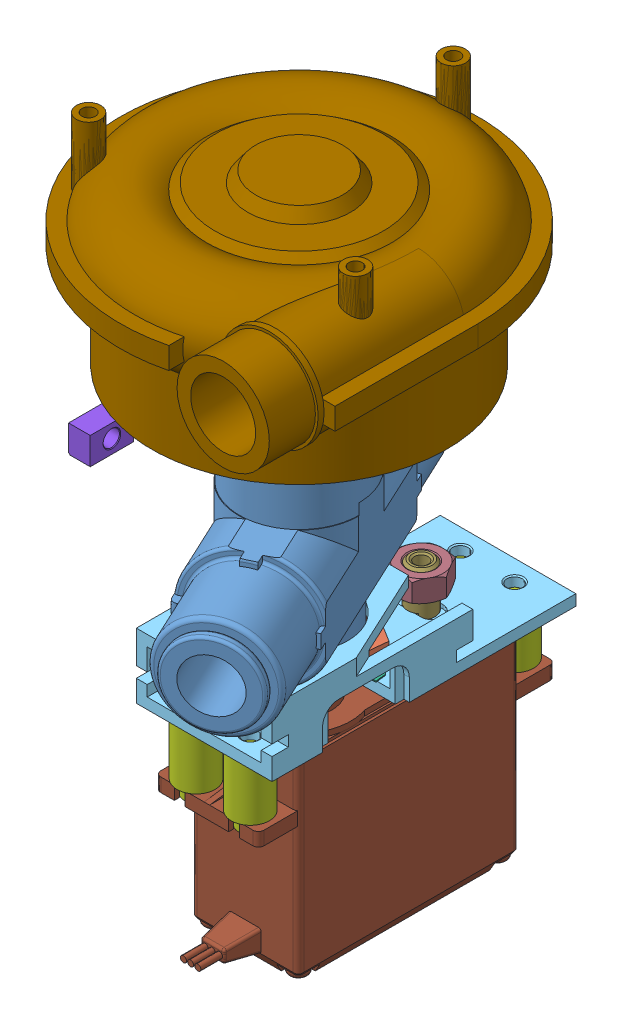
SolidWorks assembly компрессор_v3, configuration По умолчанию. Lengths in mm.
Overall size (66 124.61 75.54).
25 component instances, 20 part files, 46 mates.
Components (placement in the parent):
- 326-4F6SMC6SMC_WO_GRIP_CUT-1: 326-4F6SMC6SMC_WO_GRIP_CUT [По умолчанию] at (-17.3525 27.3268 -50.2596) x (0.422618 0 0.906308) z (0 -1 0) size (66.8 22.11 40.11)
- фланец_v3-1: фланец_v3 [По умолчанию] at (-3.2366 53.3268 5.012) x (1 0 0) z (0 1 0) (suppressed, hidden)
- гайка_18-1: гайка_18 [По умолчанию] at (-3.2366 14.83 -19.988) x (-0.866025 0 -0.5) z (-0.5 0 0.866025) size (24.25 4 21) (hidden)
- гайка_22-1: гайка_22 [По умолчанию] at (-3.2366 39.3268 -19.988) x (0.866025 0 -0.5) z (0.5 0 0.866025) (suppressed, hidden)
- apc10004_6_0-1: apc10004_6_0 [По умолчанию] at (15 66.2108 207.372) x (0.004188 0.999991 0) z (0 0 1) size (19.05 23.5 35.56) (suppressed, hidden)
  - APC10004-BODY-1: APC10004-BODY [По умолчанию] at origin size (19.05 19.05 35.56)
  - APC-LATCH_1-1: APC-LATCH_1 [По умолчанию] at origin size (15.11 23.5 12.49)
- ручка_крана_обрез-1: ручка_крана_обрез [По умолчанию] at (-3.2366 11.25 -19.988) x (0.678602 0 -0.734506) z (0.734506 0 0.678602) size (9.5 7 9.5)
- крестовина_2-1: крестовина_2 [По умолчанию] at (-3.2366 13.75 -19.988) x (0.418906 0 0.90803) z (0 -1 0) size (14 14 4.5)
- мостик_v5-1: мостик_v5 [По умолчанию] at (-3.2366 10.83 -2.488) x (-1 0 0) z (0 0 -1) size (25 12 56) (hidden)
- стрелка-1: стрелка [По умолчанию] at (-3.3741 8.436 -21.2304) x (-0.110025 0 -0.993929) z (0.993929 0 -0.110025) size (10 0.2 20.5) (hidden)
- EE-SX1107-1: EE-SX1107 [По умолчанию] at (6.2634 8.536 -16.9874) x (0 0 1) z (0 -1 0)
- EE-SX1107-2: EE-SX1107 [По умолчанию] at (6.2634 8.536 -22.9679) x (0 0 -1) z (0 1 0)
- сухарь1-1: сухарь1 [По умолчанию] at (9.2634 16.83 -43.488) x (0 0 1) z (-1 0 0) (suppressed, hidden)
- бобышка_серво-1: бобышка_серво [По умолчанию] at (1.7634 4.83 -5.988) x (-0.837169 0 -0.546944) z (-0.546944 0 0.837169) size (7 12.4 7)
- бобышка_серво-2: бобышка_серво [По умолчанию] at (1.7634 4.83 -54.688) x (-0.837169 0 -0.546944) z (-0.546944 0 0.837169) size (7 12.4 7)
- бобышка_серво-3: бобышка_серво [По умолчанию] at (-8.2366 4.83 -54.688) x (-0.837169 0 -0.546944) z (-0.546944 0 0.837169) size (7 12.4 7)
- бобышка_серво-4: бобышка_серво [По умолчанию] at (-8.2366 4.83 -5.988) x (-0.837169 0 -0.546944) z (-0.546944 0 0.837169) size (7 12.4 7)
- сухарь2-1: сухарь2 [По умолчанию] at (-20.7366 16.83 -2.488) x (0 0 -1) z (1 0 0) (suppressed, hidden)
- гайка_закладная-1: гайка_закладная [Default] at (-23.2366 43.8268 0.512) x (-1 0 0) z (0 0 -1) size (4 5 8) (hidden)
- BLOWER_WS7040-12-1: BLOWER_WS7040-12 [По умолчанию] at (-3.2366 87.4393 -19.988) x (0 -1 0) z (0 0 1) size (37.5 66 69)
- качалка_Al-1: качалка_Al [По умолчанию] at (-3.2366 10.75 -19.988) x (0 -1 0) z (0.90803 0 -0.418906) size (4.5 14 9)
- MG-995_2008_STEP-1: MG-995_2008_STEP [По умолчанию] at (-105.9599 -43.1903 -9.988) x (-1 0 0) z (0 0 -1) size (19.7 42.9 57.7)
- M6-M3-1: M6-M3 [По умолчанию] at (-3.2366 6.13 -42.488) x (0 1 0) z (-1 0 0) size (8 5 5)
- гайка_М5-1: гайка_М5 [По умолчанию] at (-3.2366 13.83 -42.488) x (1 0 0) z (0 -1 0) size (9.24 8 4.02)
Mates (geometry in assembly coordinates):
- Концентричный3: concentric anti-aligned: cylinder of 326-4F6SMC6SMC_WO_GRIP_CUT-1 through (-3.2366 47.9008 -19.988) axis (0 -1 0) radius 11.1125; cylinder of фланец_v3-1 through (-3.2366 38.3268 -19.988) axis (0 1 0) radius 11.25
- Расстояние10: distance = 0.5 mm anti-aligned: plane of 326-4F6SMC6SMC_WO_GRIP_CUT-1 through (-11.9976 37.8268 -38.776) normal (0 1 0); plane of фланец_v3-1 through (-28.2366 38.3268 -44.988) normal (0 -1 0)
- Концентричный7: concentric aligned: cylinder of 326-4F6SMC6SMC_WO_GRIP_CUT-1 through (-3.2366 18.5384 -19.988) axis (0 1 0) radius 8.7312; cylinder of гайка_18-1 through (-3.2366 10.83 -19.988) axis (0 1 0) radius 8.5
- Совпадение19: coincident anti-aligned: plane of фланец_v3-1 through (-10.2366 39.3268 -10.488) normal (0 1 0); plane of гайка_22-1 through (11.7634 39.3268 -28.6483) normal (0 -1 0)
- Концентричный8: concentric anti-aligned: cylinder of 326-4F6SMC6SMC_WO_GRIP_CUT-1 through (-3.2366 50.4408 -19.988) axis (0 1 0) radius 11; cylinder of гайка_22-1 through (-3.2366 44.3268 -19.988) axis (0 -1 0) radius 10.25
- Ширина4: width anti-aligned: plane of гайка_22-1 through (11.7634 44.3268 -11.3277) normal (1 0 0); plane of гайка_22-1 through (-18.2366 44.3268 -28.6483) normal (-1 0 0); plane of фланец_v3-1 through (11.7634 39.3268 -10.488) normal (-1 0 0); plane of фланец_v3-1 through (-18.2366 39.3268 -10.488) normal (1 0 0)
- Концентричный14: concentric aligned: cylinder of 326-4F6SMC6SMC_WO_GRIP_CUT-1 through (-3.2366 18.5384 -19.988) axis (0 1 0) radius 8.7312; cylinder of мостик_v5-1 through (-3.2366 4.829 -19.988) axis (0 1 0) radius 9
- Совпадение33: coincident anti-aligned: plane of 326-4F6SMC6SMC_WO_GRIP_CUT-1 through (-3.2366 16.83 -19.988) normal (0 -1 0); plane of мостик_v5-1 through (9.2634 16.83 -58.488) normal (0 1 0)
- Совпадение41: coincident anti-aligned: plane of мостик_v5-1 through (9.2634 16.83 -58.488) normal (0 1 0); plane of сухарь1-1 through (9.2634 16.83 -43.488) normal (0 -1 0)
- Совпадение43: coincident aligned: plane of мостик_v5-1 through (9.2634 4.83 -58.488) normal (1 0 0); plane of сухарь1-1 through (9.2634 20.83 -27.488) normal (1 0 0)
- Совпадение45: coincident anti-aligned: plane of мостик_v5-1 through (9.2634 4.83 -58.488) normal (0 -1 0); plane of бобышка_серво-1 through (3.6777 4.83 -8.9181) normal (0 1 0)
- Совпадение46: coincident anti-aligned: plane of мостик_v5-1 through (9.2634 4.83 -58.488) normal (0 -1 0); plane of бобышка_серво-2 through (3.6777 4.83 -57.6181) normal (0 1 0)
- Совпадение47: coincident anti-aligned: plane of мостик_v5-1 through (9.2634 4.83 -58.488) normal (0 -1 0); plane of бобышка_серво-4 through (-6.3223 4.83 -8.9181) normal (0 1 0)
- Совпадение48: coincident anti-aligned: plane of мостик_v5-1 through (9.2634 4.83 -58.488) normal (0 -1 0); plane of бобышка_серво-3 through (-6.3223 4.83 -57.6181) normal (0 1 0)
- Совпадение50: coincident anti-aligned: plane of мостик_v5-1 through (9.2634 16.83 -58.488) normal (0 1 0); plane of сухарь2-1 through (-20.7366 16.83 -2.488) normal (0 -1 0)
- Расстояние7: distance = 5 mm aligned: plane of мостик_v5-1 through (-15.7366 4.83 -58.488) normal (-1 0 0); plane of сухарь2-1 through (-20.7366 20.83 -17.488) normal (-1 0 0)
- Совпадение52: coincident aligned: plane of мостик_v5-1 through (-15.7366 16.83 -2.488) normal (0 0 1); plane of сухарь2-1 through (-20.7366 20.83 -2.488) normal (0 0 1)
- Совпадение53: coincident anti-aligned: plane of фланец_v3-1 through (-25.2366 65.3268 -44.988) normal (1 0 0); plane of гайка_закладная-1 through (-25.2366 41.3268 -7.488) normal (-1 0 0)
- Совпадение54: coincident anti-aligned: plane of фланец_v3-1 through (-25.2366 41.3268 -44.988) normal (0 1 0); plane of гайка_закладная-1 through (-21.2366 41.3268 -7.488) normal (0 -1 0)
- Параллельность5: parallel aligned: plane of фланец_v3-1 through (-28.2366 68.3268 -44.988) normal (-1 0 0); plane of мостик_v5-1 through (-15.7366 4.83 -58.488) normal (-1 0 0)
- Расстояние9: distance = 4.5 mm aligned: plane of фланец_v3-1 through (21.7634 38.3268 5.012) normal (0 0 1); plane of гайка_закладная-1 through (-21.2366 46.3268 0.512) normal (0 0 1)
- Совпадение74: coincident anti-aligned: plane of гайка_18-1 through (-13.7366 14.83 -26.0502) normal (0 1 0); plane of мостик_v5-1 through (7.2634 14.83 -58.488) normal (0 -1 0)
- Угол1: planar angle = 0.436332 rad aligned: plane of мостик_v5-1 through (9.2634 4.83 -58.488) normal (1 0 0); plane of 326-4F6SMC6SMC_WO_GRIP_CUT-1 through (-9.823 39.8268 -57.7747) normal (0.906308 0 -0.422618)
- Концентричный20: concentric anti-aligned: cylinder of 326-4F6SMC6SMC_WO_GRIP_CUT-1 through (-3.2366 50.4408 -19.988) axis (0 1 0) radius 11; cylinder of BLOWER_WS7040-12-1 through (-3.2366 89.1143 -19.988) axis (0 -1 0) radius 12.925
- Расстояние11: distance = 17 mm anti-aligned: plane of BLOWER_WS7040-12-1 through (-3.2366 55.4393 -19.988) normal (0 -1 0); cylinder of 326-4F6SMC6SMC_WO_GRIP_CUT-1 through (3.3651 27.3268 -5.8306) axis (-0.422618 0 -0.906308) radius 11.1125
- Параллельность6: parallel aligned: plane of мостик_v5-1 through (9.2634 4.83 -58.488) normal (1 0 0); plane of BLOWER_WS7040-12-1 through (29.7634 75.4393 -19.988) normal (1 0 0)
- Совпадение75: coincident anti-aligned: plane of 326-4F6SMC6SMC_WO_GRIP_CUT-1 through (14.3006 14.25 -28.1657) normal (0 -1 0); plane of ручка_крана_обрез-1 through (-1.0773 14.25 -22.3252) normal (0 1 0)
- Концентричный21: concentric aligned: cylinder of 326-4F6SMC6SMC_WO_GRIP_CUT-1 through (-3.2366 14.25 -19.988) axis (0 -1 0) radius 7.5; cylinder of ручка_крана_обрез-1 through (-3.2366 18.25 -19.988) axis (0 -1 0) radius 4.75
- Концентричный29: concentric anti-aligned: cylinder of качалка_Al-1 through (-3.2366 10.75 -19.988) axis (0 1 0) radius 4.5; cylinder of MG-995_2008_STEP-1 through (-3.2366 9.73 -19.988) axis (0 -1 0) radius 3
- Ширина8: width anti-aligned: plane of мостик_v5-1 through (-15.7366 4.83 -58.488) normal (-1 0 0); plane of мостик_v5-1 through (9.2634 4.83 -58.488) normal (1 0 0); plane of MG-995_2008_STEP-1 through (6.6134 9.6131 -50.688) normal (1 0 0); plane of MG-995_2008_STEP-1 through (-13.0866 -33.2869 -50.688) normal (-1 0 0)
- Концентричный30: concentric aligned: cylinder of бобышка_серво-2 through (1.7634 4.83 -54.688) axis (0 1 0) radius 2.2; cylinder of MG-995_2008_STEP-1 through (1.7634 -8.17 -54.688) axis (0 1 0) radius 2.3
- Концентричный31: concentric aligned: cylinder of бобышка_серво-3 through (-8.2366 4.83 -54.688) axis (0 1 0) radius 2.2; cylinder of MG-995_2008_STEP-1 through (-8.2366 -8.17 -54.688) axis (0 1 0) radius 2.3
- Концентричный32: concentric aligned: cylinder of бобышка_серво-1 through (1.7634 4.83 -5.988) axis (0 1 0) radius 2.2; cylinder of MG-995_2008_STEP-1 through (1.7634 -33.17 -5.988) axis (0 1 0) radius 2.3
- Концентричный33: concentric aligned: cylinder of бобышка_серво-4 through (-8.2366 4.83 -5.988) axis (0 1 0) radius 2.2; cylinder of MG-995_2008_STEP-1 through (-8.2366 -33.17 -5.988) axis (0 1 0) radius 2.3
- Концентричный34: concentric aligned: cylinder of мостик_v5-1 through (-3.2366 4.83 -42.488) axis (0 -1 0) radius 1.8; cylinder of M6-M3-1 through (-3.2366 6.13 -42.488) axis (0 -1 0) radius 1.25
- Параллельность11: parallel anti-aligned: plane of мостик_v5-1 through (-1.2366 6.13 -40.488) normal (0 0 -1); plane of M6-M3-1 through (-3.2366 7.13 -40.488) normal (0 0 1)
- Совпадение84: coincident anti-aligned: plane of мостик_v5-1 through (-1.2366 6.13 -42.488) normal (0 1 0); plane of M6-M3-1 through (-3.2366 6.13 -43.738) normal (0 -1 0)
- Концентричный35: concentric anti-aligned: cylinder of M6-M3-1 through (-3.2366 6.13 -42.488) axis (0 -1 0) radius 2.5; cylinder of гайка_М5-1 through (-3.2366 13.83 -42.488) axis (0 1 0) radius 2.1
- Расстояние15: distance = 3 mm anti-aligned: plane of мостик_v5-1 through (7.2634 6.83 -58.488) normal (0 1 0); plane of гайка_М5-1 through (1.3822 9.83 -42.488) normal (0 -1 0)
- Параллельность12: parallel aligned: plane of мостик_v5-1 through (9.2634 4.83 -58.488) normal (1 0 0); plane of MG-995_2008_STEP-1 through (6.6134 9.73 -50.688) normal (1 0 0)
- Концентричный36: concentric anti-aligned: cylinder of мостик_v5-1 through (-8.2366 4.83 -5.988) axis (0 -1 0) radius 1.4224; cylinder of бобышка_серво-4 through (-8.2366 4.83 -5.988) axis (0 1 0) radius 3.5
- Совпадение86: coincident anti-aligned: plane of бобышка_серво-4 through (-7.0333 -5.17 -7.8298) normal (0 -1 0); plane of MG-995_2008_STEP-1 through (-3.2366 -5.17 -2.988) normal (0 1 0)
- Совпадение88: coincident anti-aligned: plane of ручка_крана_обрез-1 through (-3.2366 13.75 -19.988) normal (0 -1 0); plane of крестовина_2-1 through (10.8755 13.75 -26.4984) normal (0 1 0)
- Совпадение89: coincident anti-aligned: plane of крестовина_2-1 through (10.8755 9.25 -26.4984) normal (0 -1 0); plane of качалка_Al-1 through (-0.4072 9.25 -24.5972) normal (0 1 0)
- Ширина10: width anti-aligned: plane of крестовина_2-1 through (4.3763 13.75 -20.1963) normal (-0.418906 0 -0.90803); plane of крестовина_2-1 through (1.8629 13.75 -25.6444) normal (0.418906 0 0.90803); plane of ручка_крана_обрез-1 through (-5.6603 25.8514 -15.566) normal (0.418906 0 0.90803); plane of ручка_крана_обрез-1 through (-8.1737 25.8514 -21.0142) normal (-0.418906 0 -0.90803)
- Ширина11: width anti-aligned: plane of качалка_Al-1 through (0.6038 18.8442 -14.0507) normal (0.90803 0 -0.418906); plane of качалка_Al-1 through (-1.2123 18.8442 -13.2129) normal (-0.90803 0 0.418906); plane of крестовина_2-1 through (-5.2609 9.25 -26.7631) normal (-0.90803 0 0.418906); plane of крестовина_2-1 through (-7.0769 9.25 -25.9253) normal (0.90803 0 -0.418906)
